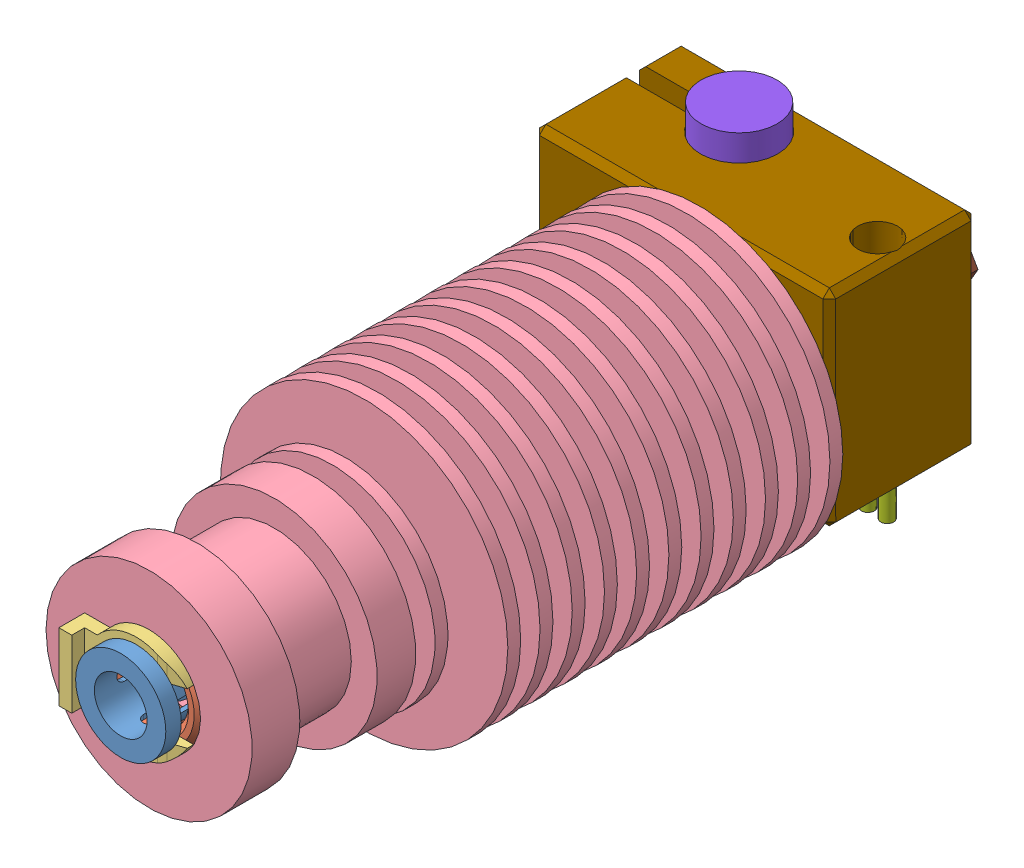
SolidWorks assembly e3D V6, configuration Default. Lengths in mm.
Overall size (27.29 22.3 64.5).
22 component instances, 14 part files, 0 mates.
Components (placement in the parent):
- e3D V6 1.75mm Hotend Assembly Mockup.step-1: e3D V6 1.75mm Hotend Assembly Mockup.step [Default] at origin size (38.97 30.07 64.5)
  - V6-175-SINK.step-1: V6-175-SINK.step [Default] at (-0.0711 0 18.6) x (1 0.000031 0) z (0 0 1) size (22.3 22.3 44.95)
    - PTFE Tube Retainer.step-1: PTFE Tube Retainer.step [Default] at (0 0 1) x (-0.000024 -1 0) z (0 0 1) size (8 9 6.78)
      - Collet.step-1: Collet.step [Default] at (0 0 43.9) x (0 1 0) z (0 0 1) size (7 7 6.78)
      - Coupling.step-1: Coupling.step [Default] at (0 0 41.7) x (-0.000024 1 0) z (0 0 1) size (8 8 3.48)
      - Collet Clip.step-1: Collet Clip.step [Default] at (0 0 41.7) size (8 8.46 2)
    - V6-175-SINK-0.step-1: V6-175-SINK-0.step [Default] at origin size (22.3 22.3 42.75)
  - V6-Heatblock.step-1: V6-Heatblock.step [Default] at (-0.071 0.0711 5) x (1 0.000009 0) z (0 0 1) size (24.2 21 13.2)
    - M3x10 rounded head screw - 92095A182 (1).step-1: M3x10 rounded head screw - 92095A182 (1).step [Default] at (-12.5025 0 -1.6476) x (0.335243 0.942132 0) z (0 0 -1) size (5.7 5.7 11.65)
    - M3x4 flat tip set screw - 92605A098.step-1: M3x4 flat tip set screw - 92605A098.step [Default] at (6.0115 0 2.0029) x (-1 0.000002 0) z (0 0 -1) size (4.15 4.13 4)
    - Thermistor.step-1: Thermistor.step [Default] at (-0.0065 -2.7408 13.5951) x (1 0 0.000823) z (-0.000823 0 1) size (3 13.5 3)
    - Heater Cartridge.step-1: Heater Cartridge.step [Default] at (0.0988 0 0.1652) x (0.999682 0 0.025219) z (-0.025219 0 0.999682) size (5.9 21 5.9)
    - V6-Heatblock-1.step-1: V6-Heatblock-1.step [Default] at origin size (23 16 11.6)
  - Fan Assembly.step-1: Fan Assembly.step [Default] at (0 -26 15) size (33.65 30.07 30.1) (hidden)
    - Fan Shroud.step-1: Fan Shroud.step [Default] at (-16.2408 26 3.6) x (0 -1 0) z (0 0 1) size (30.07 22.05 30.1)
    - 30x10mm box fan.step-1: 30x10mm box fan.step [Default] at (-26.2408 26 18.6) x (0 -1 0) z (0 0 1) size (30 10 30)
    - M3x16 rounded head screw - 92095A184.step-1: M3x16 rounded head screw - 92095A184.step [Default] at (-27.8908 14 6.6) x (0 -1 0) z (-1 0 0) size (5.7 5.7 17.65)
    - M3x16 rounded head screw - 92095A184.step-2: M3x16 rounded head screw - 92095A184.step [Default] at (-27.8908 38 6.6) x (0 0 -1) z (-1 0 0) size (5.7 5.7 17.65)
    - M3x16 rounded head screw - 92095A184.step-3: M3x16 rounded head screw - 92095A184.step [Default] at (-27.8908 38 30.6) x (0 1 0) z (-1 0 0) size (5.7 5.7 17.65)
    - M3x16 rounded head screw - 92095A184.step-4: M3x16 rounded head screw - 92095A184.step [Default] at (-27.8908 14 30.6) x (0 0 1) z (-1 0 0) size (5.7 5.7 17.65)
  - V6-Heatbreak.step-1: V6-Heatbreak.step [Default] at (-0.071 0.0711 11.5) x (-1 -0.000034 0) z (0 0 1) size (6.99 6.98 22.15)
  - V6-175-Nozzle 0.4mm.step-1: V6-175-Nozzle 0.4mm.step [Default] at (-0.071 0.0711 1) x (1 0.000007 0) z (0 0 1) size (8.08 7 12.55)
